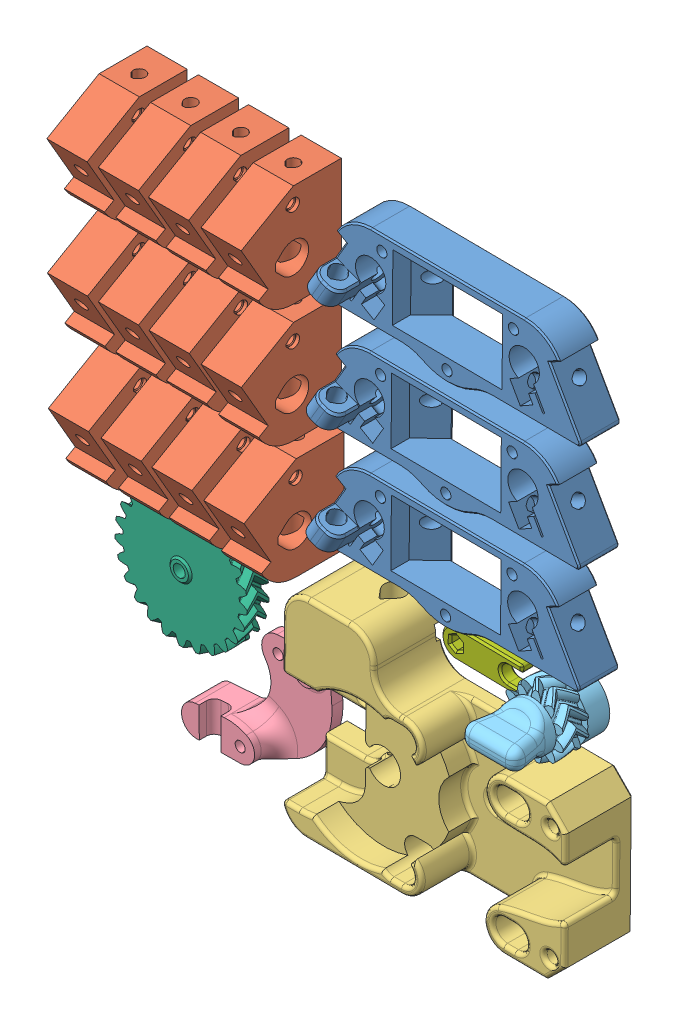
SolidWorks assembly 1200b, configuration Default. Lengths in mm.
Overall size (200 200 27.79).
20 component instances, 7 part files, 37 mates.
Components (placement in the parent):
- 1285-4: 1285 [Default] at (31.5833 67.7144 -11) x (-0.999962 0.008727 0) z (0 0 1) size (72.87 26 17.5)
- 1305-28: 1305 [Default] at (-50.0683 48.1256 -18.5) x (0 0 -1) z (-0.000396 1 0) size (27.79 11 28)
- 1305-41: 1305 [Default] at (-36.1157 48.2658 -18.5) x (0 0 -1) z (-0.000396 1 0) size (27.79 11 28)
- 1305-42: 1305 [Default] at (-22.2433 48.4501 -18.5) x (0 0 -1) z (-0.000396 1 0) size (27.79 11 28)
- 1305-43: 1305 [Default] at (-8.0154 47.5283 -18.5) x (0 0 -1) z (-0.000396 1 0) size (27.79 11 28)
- 1285-6: 1285 [Default] at (31.1755 9.3974 -11) x (-0.999962 0.008727 0) z (0 0 1) size (72.87 26 17.5)
- 1285-7: 1285 [Default] at (31.2343 38.3274 -11) x (-0.999962 0.008727 0) z (0 0 1) size (72.87 26 17.5)
- 1305-44: 1305 [Default] at (-7.2648 15.6292 -18.5) x (0 0 -1) z (-0.000396 1 0) size (27.79 11 28)
- 1305-45: 1305 [Default] at (-21.4993 16.3666 -18.5) x (0 0 -1) z (-0.000396 1 0) size (27.79 11 28)
- 1305-46: 1305 [Default] at (-35.3717 16.3666 -18.5) x (0 0 -1) z (-0.000396 1 0) size (27.79 11 28)
- 1305-47: 1305 [Default] at (-49.7971 16.1822 -18.5) x (0 0 -1) z (-0.000396 1 0) size (27.79 11 28)
- 1305-48: 1305 [Default] at (-8.0438 79.8715 -18.5) x (0 0 -1) z (-0.000396 1 0) size (27.79 11 28)
- 1305-49: 1305 [Default] at (-22.4102 79.889 -18.5) x (0 0 -1) z (-0.000396 1 0) size (27.79 11 28)
- 1305-50: 1305 [Default] at (-36.1157 80.1018 -18.5) x (0 0 -1) z (-0.000396 1 0) size (27.79 11 28)
- 1305-51: 1305 [Default] at (-50.1899 79.8715 -18.5) x (0 0 -1) z (-0.000396 1 0) size (27.79 11 28)
- 1306-1: 1306 [Default] at (39.6821 -46.4019 -11) x (0.008727 0.999962 0) z (0 0 1) size (57.6 77.5 18.81)
- 1309-1: 1309 [Default] at (-13.7451 -41.9976 -8) x (0.070151 -0.997536 0) z (0 0 -1) size (28.5 35.3 9.8)
- 1310-1: 1310 [ISO - RH Helical gear 1M 17T 45HA 20PA 12FW ---17A75H50L0.8N] at (56.9711 -14.4375 -1.5) x (0 0 -1) z (1 0 0) size (25.5 17.1 17.1)
- 1311-1: 1311 [ISO - RH Helical gear 1M 17T 45HA 20PA 12FW ---17A75H50L0.8N] at (-46.2667 -32.9532 -11) x (0 0 1) z (-1 0 0) size (9 36.33 36.3)
- 1320-1: 1320 [Default] at (40.4981 -15.4768 -11) x (0.017452 0.999848 0) z (0 0 1) size (8 22 3.6)
Mates (geometry in assembly coordinates):
- Coincident1: coincident anti-aligned: plane of ? through (52.0632 10.7688 0) normal (0 0 -1); plane of assembly through (0 0 0) normal (0 0 1)
- Coincident29: coincident aligned: plane of ? through (33.5097 39.5764 0) normal (0 0 -1); plane of ? through (73.2654 89.0664 0) normal (0 0 -1)
- Coincident31: coincident aligned: plane of ? through (52.0632 10.7688 0) normal (0 0 -1); plane of 1285-4 through (51.6613 -23.1692 0) normal (0 0 -1)
- Coincident35: coincident aligned: plane of ? through (51.0873 18.7836 0) normal (0 0 -1); plane of ? through (94.3378 19.2472 0) normal (0 0 -1)
- Coincident42: coincident aligned: plane of ? through (33.5097 39.5764 0) normal (0 0 -1); plane of ? through (-6.7321 -35.3415 0) normal (0 0 -1)
- Coincident46: coincident aligned: plane of ? through (52.0632 10.7688 0) normal (0 0 -1); plane of 1305-28 through (-75.02 81.5932 0) normal (0 0 -1)
- Coincident47: coincident aligned: plane of ? through (52.0632 10.7688 0) normal (0 0 -1); plane of ? through (21.3898 38.591 0) normal (0 0 -1)
- Coincident52: coincident aligned: plane of ? through (52.0632 10.7688 0) normal (0 0 -1); plane of ? through (37.5311 19.282 0) normal (0 0 -1)
- Coincident56: coincident aligned: plane of ? through (52.0632 10.7688 0) normal (0 0 -1); plane of ? through (35.8059 32.659 0) normal (0 0 -1)
- Coincident58: coincident aligned: plane of ? through (32.9135 41.1995 0) normal (0 0 -1); plane of ? through (36.2565 -86.3563 0) normal (0 0 -1)
- Coincident60: coincident aligned: plane of ? through (32.9135 41.1995 0) normal (0 0 -1); plane of ? through (-10.743 10.0798 0) normal (0 0 -1)
- Coincident61: coincident aligned: plane of ? through (33.5097 39.5764 0) normal (0 0 -1); plane of ? through (23.1013 9.8479 0) normal (0 0 -1)
- Coincident64: coincident aligned: plane of ? through (33.5097 39.5764 0) normal (0 0 -1); plane of ? through (-1.9841 16.7196 0) normal (0 0 -1)
- Coincident67: coincident aligned: plane of ? through (52.0632 10.7688 0) normal (0 0 -1); plane of ? through (21.3898 38.591 0) normal (0 0 -1)
- Coincident68: coincident aligned: plane of ? through (52.0632 10.7688 0) normal (0 0 -1); plane of ? through (20.7495 8.8205 0) normal (0 0 -1)
- Coincident71: coincident aligned: plane of ? through (52.0632 10.7688 0) normal (0 0 -1); plane of 1285-4 through (51.6613 -23.1692 0) normal (0 0 -1)
- Coincident72: coincident aligned: plane of ? through (52.0632 10.7688 0) normal (0 0 -1); plane of ? through (-60.5408 -24.7056 0) normal (0 0 -1)
- Coincident73: coincident aligned: plane of 1285-7 through (52.2335 38.1441 -11) normal (0 0 -1); plane of 1305-51 through (-61.1903 80.8671 -11) normal (0 0 -1)
- Coincident74: coincident aligned: plane of 1285-7 through (52.2335 38.1441 -11) normal (0 0 -1); plane of 1305-50 through (-47.1161 81.0974 -11) normal (0 0 -1)
- Coincident75: coincident aligned: plane of 1285-7 through (52.2335 38.1441 -11) normal (0 0 -1); plane of 1305-49 through (-33.4106 80.8846 -11) normal (0 0 -1)
- Coincident76: coincident aligned: plane of 1305-43 through (-19.0158 48.524 -11) normal (0 0 -1); plane of 1285-7 through (52.2335 38.1441 -11) normal (0 0 -1)
- Coincident77: coincident aligned: plane of 1285-7 through (52.2335 38.1441 -11) normal (0 0 -1); plane of 1305-44 through (-18.2652 16.6248 -11) normal (0 0 -1)
- Coincident78: coincident aligned: plane of 1285-7 through (52.2335 38.1441 -11) normal (0 0 -1); plane of 1305-45 through (-32.4997 17.3622 -11) normal (0 0 -1)
- Coincident79: coincident aligned: plane of 1285-7 through (52.2335 38.1441 -11) normal (0 0 -1); plane of 1305-46 through (-46.3721 17.3622 -11) normal (0 0 -1)
- Coincident80: coincident aligned: plane of 1285-7 through (52.2335 38.1441 -11) normal (0 0 -1); plane of 1305-47 through (-60.7975 17.1779 -11) normal (0 0 -1)
- Coincident81: coincident aligned: plane of 1305-42 through (-33.2437 49.4458 -11) normal (0 0 -1); plane of 1285-7 through (52.2335 38.1441 -11) normal (0 0 -1)
- Coincident82: coincident aligned: plane of 1305-41 through (-47.1161 49.2614 -11) normal (0 0 -1); plane of 1285-7 through (52.2335 38.1441 -11) normal (0 0 -1)
- Coincident83: coincident aligned: plane of 1305-28 through (-61.0687 49.1213 -11) normal (0 0 -1); plane of 1285-7 through (52.2335 38.1441 -11) normal (0 0 -1)
- Coincident84: coincident aligned: plane of 1285-7 through (52.2335 38.1441 -11) normal (0 0 -1); plane of 1305-48 through (-19.0442 80.8671 -11) normal (0 0 -1)
- Coincident85: coincident aligned: plane of 1285-6 through (52.1747 9.2141 -11) normal (0 0 -1); plane of 1285-7 through (52.2335 38.1441 -11) normal (0 0 -1)
- Coincident86: coincident aligned: plane of 1285-4 through (52.5825 67.5312 -11) normal (0 0 -1); plane of 1285-7 through (52.2335 38.1441 -11) normal (0 0 -1)
- Coincident87: coincident aligned: plane of 1285-7 through (52.2335 33.9547 -11) normal (0 0 -1); plane of ? through (25.0208 -43.4941 -11) normal (0 0 -1)
- Coincident88: coincident aligned: plane of 1285-6 through (52.1747 9.2141 -11) normal (0 0 -1); plane of 1306-1 through (4.6031 -46.0958 -11) normal (0 0 -1)
- Coincident89: coincident aligned: plane of 1285-6 through (52.1747 9.2141 -11) normal (0 0 -1); plane of 1309-1 through (-12.9471 -41.9415 -11) normal (0 0 -1)
- Coincident90: coincident aligned: plane of 1285-6 through (52.1747 9.2141 -11) normal (0 0 -1); plane of 1310-1 through (56.9711 -14.4375 -11) normal (0 0 -1)
- Coincident91: coincident aligned: plane of 1285-6 through (52.1747 9.2141 -11) normal (0 0 -1); plane of 1320-1 through (26.5002 -15.2324 -11) normal (0 0 -1)
- Coincident92: coincident aligned: plane of 1285-6 through (52.1747 9.2141 -11) normal (0 0 -1); plane of 1311-1 through (-46.2667 -32.9532 -11) normal (0 0 -1)
